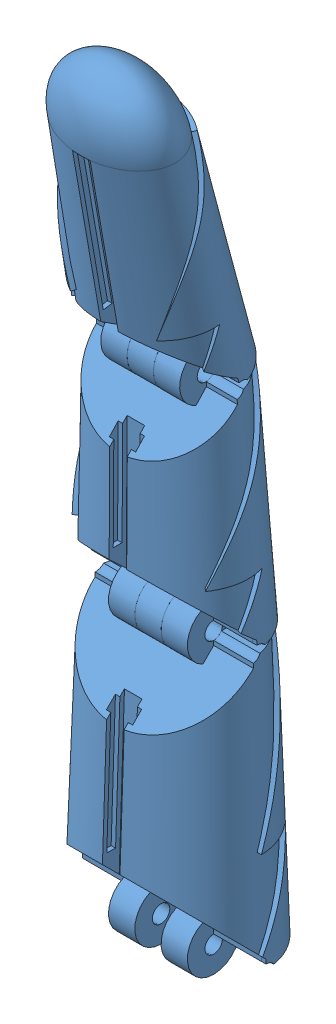
SolidWorks assembly Ensamblaje1, configuration Predeterminado. Lengths in mm.
Overall size (21.01 93.04 21.44).
3 component instances, 1 part files, 9 mates.
Components (placement in the parent):
- dedo-1: dedo [falange 1] at origin size (21.01 37 15.86)
- dedo-2: dedo [falange 2] at (0 30.9997 0.0169) x (1 0 0) z (0 -0.033857 0.999427) size (18.97 32 13.83)
- dedo-3: dedo [falange 3] at (0 56.9739 0.9857) x (1 0 0) z (0 -0.210722 0.977546) size (16.97 35.52 11.84)
Mates (geometry in assembly coordinates):
- Coincidente1: coincident aligned: plane of dedo-1 through (0 0 0) normal (0 1 0)
- Coincidente2: coincident aligned: plane of dedo-1 through (0 0 0) normal (1 0 0)
- Coincidente3: coincident aligned: plane of dedo-1 through (0 0 0) normal (0 0 1)
- Coincidente4: coincident aligned: plane of dedo-1 through (0 0 0) normal (1 0 0); plane of dedo-2 through (0 30.9997 0.0169) normal (1 0 0)
- Coincidente5: coincident aligned: plane of dedo-2 through (0 30.9997 0.0169) normal (1 0 0); plane of dedo-3 through (0 56.9739 0.9857) normal (1 0 0)
- Concéntrica1: concentric anti-aligned: cylinder of dedo-1 through (1.5 30.5 0) axis (-1 0 0) radius 3; cylinder of dedo-2 through (-9.496 30.5 0) axis (1 0 0) radius 1
- Concéntrica2: concentric anti-aligned: cylinder of dedo-2 through (1.5 56.4851 0.8803) axis (-1 0 0) radius 3; cylinder of dedo-3 through (-8.4399 56.4851 0.8803) axis (1 0 0) radius 1
- Ángulo límite1: limit planar angle = 0.033864 rad anti-aligned: plane of dedo-2 through (0 30.9997 0.0169) normal (0 -0.999427 -0.033857); plane of dedo-1 through (9 30 0.0135) normal (0 1 0)
- Ángulo límite2: limit planar angle = 0.17845 rad anti-aligned: plane of dedo-3 through (0 56.9739 0.9857) normal (0 -0.977546 -0.210722); plane of dedo-2 through (8 55.9851 0.8713) normal (0 0.999427 0.033857)
